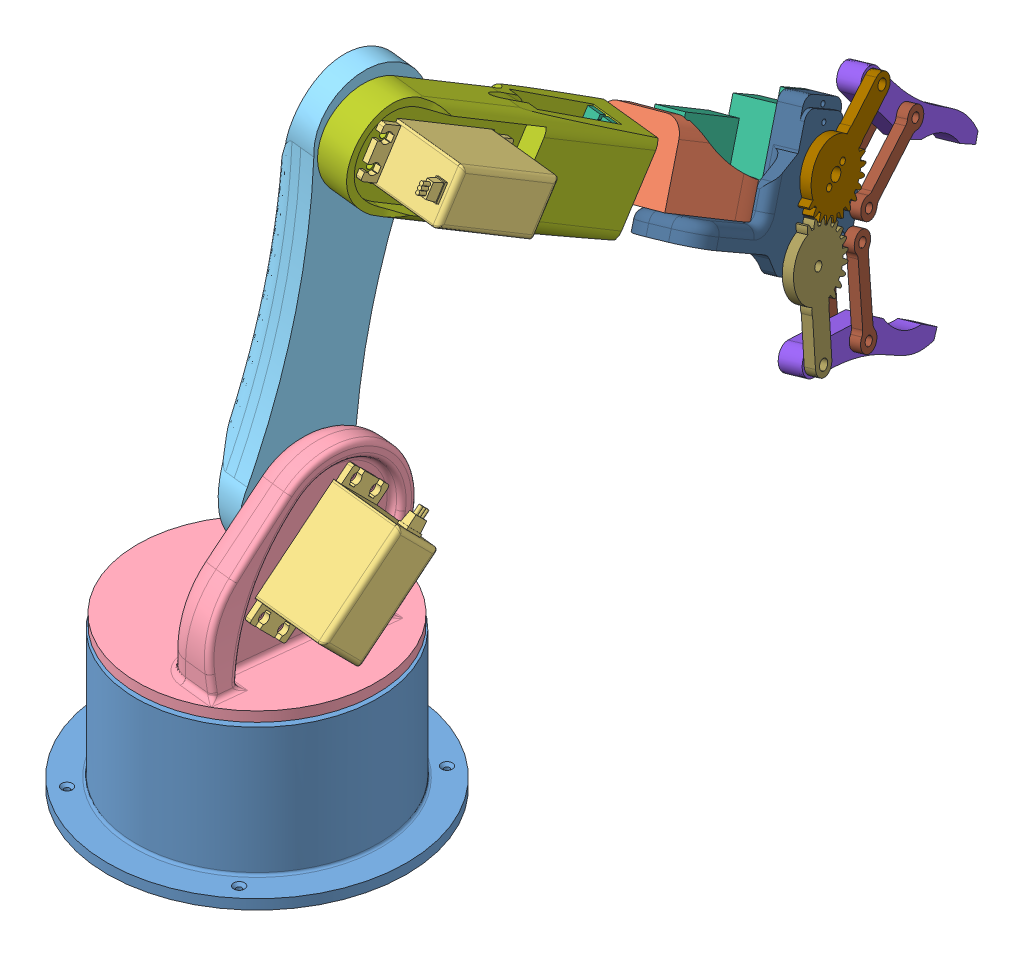
SolidWorks assembly Assem3, configuration Default. Lengths in mm.
Overall size (168309.1 243417.79 332794.81).
21 component instances, 12 part files, 29 mates.
Components (placement in the parent):
- BASE of the robot-1: BASE of the robot [Default] at origin size (121250 56000 121250)
- Part5 ARM3-1: Part5 ARM3 [Default] at (30363.9754 154464.1104 -122045.7649) x (0.969385 0.243541 -0.031321) z (-0.226989 0.840158 -0.492555) size (33000 46000.01 28000.01)
- Servo Motor MG996R part 7-1: Servo Motor MG996R part 7 [Default] at (-0.1259 -12163.5201 10445.9899) x (0 0 1) z (-1 0 0) size (55800 47400 21000)
- Waist Part2-1: Waist Part2 [Default] at (-0.1259 35236.4799 195.9899) x (0.107051 0 -0.994254) z (0.994254 0 0.107051) size (97000 67780 97000)
- Arm 01 part 3-1: Arm 01 part 3 [Default] at (-15486.681 192398.3621 -42796.9583) x (-0.104269 0.226483 0.968418) z (0.024245 0.974015 -0.225182) size (46257.9 22493.15 162000)
- Servo Motor MG996R part 7-2: Servo Motor MG996R part 7 [Default] at (48834.9429 68268.7055 -1246.6833) x (-0.075696 -0.707107 0.703043) z (0.075696 -0.707107 -0.703043) size (55800 47400 21000)
- Servo MOtor micro 9g-2: Servo MOtor micro 9g [Default] at (22614.6596 162674.4142 -93075.7288) x (-0.051875 -0.874744 0.4818) z (0.994254 0 0.107051) size (32600 29900 12400)
- Servo Motor MG996R part 7-4: Servo Motor MG996R part 7 [Default] at (53480.0935 187431.3655 -44389.2743) x (0.093642 -0.484585 -0.869717) z (0.051875 0.874744 -0.4818) size (55800 47400 21000)
- Arm2 Part4-2: Arm2 Part4 [Default] at (14612.232 175559.0321 -70129.2634) x (0.093642 -0.484585 -0.869717) z (0.994254 0 0.107051) size (115000 38000 27000)
- Servo MOtor micro 9g-4: Servo MOtor micro 9g [Default] at (29205.6869 155591.4107 -149128.9711) x (-0.093642 0.484585 0.869717) z (0.969385 0.243541 -0.031321) size (32600 29900 12400)
- Assem1-4: Assem1 [Default] at (-7508.793 41434.3481 -78529.2891) x (0.422981 0.598118 0.680693) z (-0.1391 0.785157 -0.603473) size (122566.59 85847.99 113737.06)
  - Gripper-1: Gripper [Default] at (-12258.9555 72723.9583 149711.2792) x (-0.87081 0.401197 -0.284133) z (0.298495 -0.027747 -0.954008) size (65457.64 8500 20104.11)
  - part 2 Gear 2-1: part 2 Gear 2 [Default] at (4124.6682 82232.4754 122453.666) x (-0.374008 0.062963 0.925286) z (-0.390629 -0.915571 -0.095593) size (49380 26720 4000)
  - Part1 Gripper Base-1: Part1 Gripper Base [Default] at (-25974.9204 84532.3811 92661.2978) x (0.071223 -0.133592 0.988474) z (-0.917789 0.379318 0.117395) size (53300 28000 77000)
  - Part4 gripper link-1: Part4 gripper link [Default] at (-30869.0927 97298.0373 79312.4358) x (0.442883 -0.277955 0.852406) z (-0.807009 0.290638 0.514068) size (39000 4000 8000)
  - Gear 1&2-4: Gear 1&2 [Default] at (646.2599 82163.8202 95481.3476) x (-0.431094 0.273696 -0.859796) z (0.390629 0.915571 0.095593) size (49380 26720 4000)
  - Servo MOtor micro 9g-1: Servo MOtor micro 9g [Default] at (-9594.2758 48544.8099 124048.7429) x (0.071223 -0.133592 0.988474) z (-0.917789 0.379318 0.117395) size (32600 29900 12400)
  - Gripper-2: Gripper [Default] at (-12609.8772 90579.9838 69042.635) x (-0.829964 0.305366 0.466809) z (0.398206 -0.261688 0.879176) size (65457.64 8500 20104.11)
  - Part4 gripper link-2: Part4 gripper link [Default] at (-28096.419 89332.6559 144272.9052) x (0.376417 -0.064101 -0.92423) z (0.840071 -0.397014 0.369676) size (39000 4000 8000)
  - Part4 gripper link-3: Part4 gripper link [Default] at (-21310.37 75900.8842 114426.8493) x (-0.376417 0.064101 0.92423) z (-0.840071 0.397014 -0.369676) size (39000 4000 8000)
  - Part4 gripper link-4: Part4 gripper link [Default] at (-22022.5974 77236.8062 104542.1114) x (-0.442883 0.277955 -0.852406) z (0.807009 -0.290638 -0.514068) size (39000 4000 8000)
Mates (geometry in assembly coordinates):
- Coincident1: coordinate: point of BASE of the robot-1
- Concentric1: concentric aligned: cylinder of BASE of the robot-1 through (-0.1259 -18163.5201 195.9899) axis (0 -1 0) radius 45000; cylinder of Waist Part2-1 through (-0.1259 39236.4799 195.9899) axis (0 -1 0) radius 48500
- Parallel1: parallel aligned: plane of BASE of the robot-1 through (12999.8741 -22163.5201 -11054.0101) normal (0 0 1); plane of Servo Motor MG996R part 7-1 through (10249.8741 24836.4799 30945.9899) normal (0 0 1)
- Concentric2: concentric anti-aligned: circle of BASE of the robot-1; circle of Servo Motor MG996R part 7-1
- Coincident2: coincident anti-aligned: plane of BASE of the robot-1 through (12999.8741 15836.4799 195.9899) normal (0 1 0); plane of Servo Motor MG996R part 7-1 through (9249.8741 15836.4799 -16854.0101) normal (0 -1 0)
- Concentric3: concentric aligned: cylinder of BASE of the robot-1 through (4999.8741 8636.4799 -13554.0101) axis (0 1 0) radius 1300; cylinder of Servo Motor MG996R part 7-1 through (4999.8741 11436.4799 -13554.0101) axis (0 1 0) radius 2100
- Concentric4: concentric aligned: cylinder of BASE of the robot-1 through (-5000.1259 8636.4799 34445.9899) axis (0 1 0) radius 1300; cylinder of Servo Motor MG996R part 7-1 through (-5000.1259 11436.4799 34445.9899) axis (0 1 0) radius 2100
- Coincident4: coincident anti-aligned: plane of Servo Motor MG996R part 7-1 through (-0.1259 35236.4799 195.9899) normal (0 1 0); plane of Waist Part2-1 through (-0.1259 35236.4799 195.9899) normal (0 -1 0)
- Concentric10: concentric aligned: cylinder of Waist Part2-1 through (39575.0547 88774.8022 -11367.086) axis (-0.974818 0 -0.223002) radius 1300; cylinder of Servo Motor MG996R part 7-2 through (28657.0943 88774.8022 -13864.7131) axis (-0.974818 0 -0.223002) radius 2100
- Coincident9: coincident anti-aligned: plane of Waist Part2-1 through (17693.5937 47096.4799 3567.4584) normal (0.974818 0 0.223002); plane of Servo Motor MG996R part 7-2 through (21878.5305 94113.4584 -14726.2943) normal (-0.974818 0 -0.223002)
- Concentric11: concentric aligned: cylinder of Waist Part2-1 through (41151.92 81703.7344 -18260.0894) axis (-0.974818 0 -0.223002) radius 1300; cylinder of Servo Motor MG996R part 7-2 through (30233.9596 81703.7344 -20757.7165) axis (-0.974818 0 -0.223002) radius 2100
- Concentric12: concentric aligned: cylinder of Waist Part2-1 through (41151.92 81703.7344 -18260.0894) axis (-0.974818 0 -0.223002) radius 1300; cylinder of Servo Motor MG996R part 7-2 through (30233.9596 81703.7344 -20757.7165) axis (-0.974818 0 -0.223002) radius 2100
- Coincident10: coincident anti-aligned: plane of Arm 01 part 3-1 through (18346.2708 176824.6163 -75856.579) normal (0.974819 0.000743 0.222998); plane of Servo Motor MG996R part 7-2 through (4076.6714 75516.55 -13140.7929) normal (-0.974818 0 -0.223002)
- Concentric13: concentric anti-aligned: cylinder of Arm 01 part 3-1 through (4076.6725 75517.61 -13140.7992) axis (-0.974819 -0.000743 -0.222998) radius 3750; cylinder of Servo Motor MG996R part 7-2 through (4076.6714 75516.55 -13140.7929) axis (0.974818 0 0.223002) radius 10500
- Concentric19: concentric anti-aligned: cylinder of Servo Motor MG996R part 7-4 through (18362.9634 177015.439 -75957.7959) axis (0.974818 -0.00004 0.223002) radius 10500; cylinder of Arm2 Part4-2 through (26161.5065 177015.1225 -74173.7765) axis (-0.974818 0.00004 -0.223002) radius 9000
- Parallel3: parallel anti-aligned: plane of Servo Motor MG996R part 7-4 through (25425.2865 172552.9104 -60194.0898) normal (-0.101524 -0.890436 0.443639); plane of Arm2 Part4-2 through (39868.0696 165611.8927 -57859.3971) normal (0.101524 0.890436 -0.443639)
- Coincident14: coincident anti-aligned: plane of Servo Motor MG996R part 7-4 through (41451.3901 151688.9317 -100657.1395) normal (-0.974818 0.00004 -0.223002); plane of Arm2 Part4-2 through (41834.5462 161199.7697 -102330.3555) normal (0.974818 -0.00004 0.223002)
- Coincident15: coincident anti-aligned: plane of Arm 01 part 3-1 through (18346.2708 176824.6163 -75856.579) normal (0.974819 0.000743 0.222998); plane of Servo Motor MG996R part 7-4 through (18362.9634 177015.439 -75957.7959) normal (-0.974818 0.00004 -0.223002)
- Concentric20: concentric anti-aligned: cylinder of Arm 01 part 3-1 through (18346.2708 176824.6163 -75856.579) axis (-0.974819 -0.000743 -0.222998) radius 3750; cylinder of Servo Motor MG996R part 7-4 through (18362.9634 177015.439 -75957.7959) axis (0.974818 -0.00004 0.223002) radius 10500
- Concentric22: concentric anti-aligned: cylinder of Servo MOtor micro 9g-2 through (48298.8033 140046.4201 -155254.9404) axis (-0.198552 0.455108 0.868017) radius 2500; cylinder of Arm2 Part4-2 through (46343.0671 144529.2321 -146704.9701) axis (0.198552 -0.455108 -0.868017) radius 6500
- Coincident16: coincident anti-aligned: plane of Servo MOtor micro 9g-2 through (40531.5441 150960.3983 -149102.1147) normal (0.198552 -0.455108 -0.868017); plane of Arm2 Part4-2 through (53673.1649 157638.1685 -149597.2796) normal (-0.198552 0.455108 0.868017)
- Concentric24: concentric anti-aligned: cylinder of Part5 ARM3-1 through (48297.7211 140055.9158 -155260.3121) axis (0.198533 -0.455055 -0.868049) radius 2500; cylinder of Servo MOtor micro 9g-2 through (48298.8033 140046.4201 -155254.9404) axis (-0.198552 0.455108 0.868017) radius 2500
- Coincident17: coincident anti-aligned: plane of Part5 ARM3-1 through (52902.8341 142129.9464 -155294.3314) normal (-0.198533 0.455055 0.868049); plane of Servo MOtor micro 9g-2 through (48298.8033 140046.4201 -155254.9404) normal (0.198552 -0.455108 -0.868017)
- Concentric25: concentric aligned: cylinder of Part5 ARM3-1 through (63342.5399 111323.1754 -169013.1288) axis (-0.227013 0.840243 -0.492399) radius 6500; cylinder of Servo MOtor micro 9g-4 through (61946.4111 116490.6702 -172041.3828) axis (-0.227013 0.840243 -0.492399) radius 2500
- Parallel4: parallel anti-aligned: plane of Part5 ARM3-1 through (56392.5241 114011.2012 -179499.8728) normal (-0.198533 0.455055 0.868049); plane of Servo MOtor micro 9g-4 through (55540.6857 118227.3171 -181559.2995) normal (0.198533 -0.455055 -0.868049)
- Coincident18: coincident anti-aligned: plane of Part5 ARM3-1 through (34703.3981 109559.4898 -195374.824) normal (-0.227013 0.840243 -0.492399); plane of Servo MOtor micro 9g-4 through (54575.8813 121798.3501 -183651.9953) normal (0.227013 -0.840243 0.492399)
- Parallel5: parallel anti-aligned: plane of Servo MOtor micro 9g-2 through (53463.1315 149025.6996 -150025.9583) normal (0.974818 -0.00004 0.223002); plane of Arm2 Part4-2 through (47518.0558 171746.511 -122688.7437) normal (-0.974818 0.00004 -0.223002)
- Concentric26: concentric anti-aligned: circle of Servo MOtor micro 9g-4; cylinder of Assem1-4/Part1 Gripper Base-1 through (69218.5347 89608.3877 -156278.8407) axis (-0.227015 0.840242 -0.492399) radius 2500
- Coincident19: coincident anti-aligned: plane of Servo MOtor micro 9g-4 through (61946.4111 116490.6702 -172041.3828) normal (0.227013 -0.840243 0.492399); plane of Assem1-4/Part1 Gripper Base-1 through (74595.1735 126597.4265 -160626.5715) normal (-0.227015 0.840242 -0.492399)
